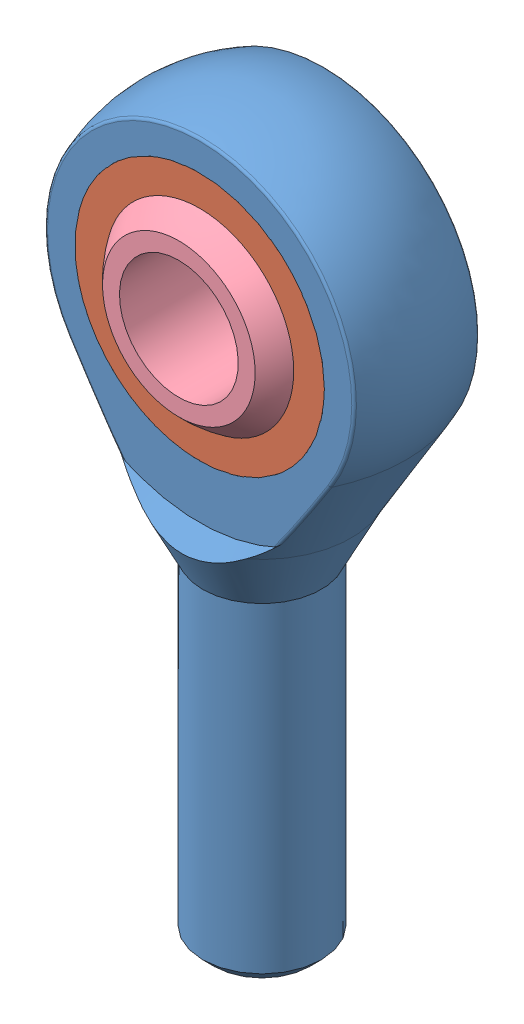
SolidWorks assembly WDS852-410, configuration 852-410. Lengths in mm.
Overall size (28 62 14.53).
4 component instances, 4 part files, 6 mates.
Components (placement in the parent):
- WDS852-410-P1-1: WDS852-410-P1 [10M] at origin size (28 62 14.53)
- WDS852-410-P2-1: WDS852-410-P2 [10] at (0 48 0) x (0 0 -1) z (1 0 0) size (10.5 21 21)
- WDS852-410-P3-1: WDS852-410-P3 [10] at (0 48 0) x (0 0 -1) z (1 0 0) size (5.5 19.6 19.6)
- WDS852-410-P4-1: WDS852-410-P4 [10] at (0 48 0) x (0 0 1) z (-0.999339 0.036344 0) size (14 19 19)
Mates (geometry in assembly coordinates):
- Concentric2: concentric anti-aligned: cylinder of 852-body-1 through (0 48 -9.5) axis (0 0 1) radius 10.5; cylinder of 852-brass-1 through (0 48 -48.3489) axis (0 0 -1) radius 10.5
- Coincident4: coincident aligned: plane of 852-body-1 through (0 48 5.25) normal (0 0 1); plane of 852-brass-1 through (0 58.5 5.25) normal (0 0 1)
- Concentric3: concentric: sphere of 852-brass-1; sphere of 852-ptfe-1
- Coincident5: coincident anti-aligned: plane of 852-brass-1 through (0 57.0933 -2.75) normal (0 0 1); plane of 852-ptfe-1 through (0 57.4062 -2.75) normal (0 0 -1)
- Concentric4: concentric: sphere of 852-ptfe-1; sphere of 852-ball-1
- Parallel1: parallel aligned: plane of 852-body-1 through (0 48 5.25) normal (0 0 1); plane of 852-ball-1 through (0.2334 54.4184 7) normal (0 0 1)
